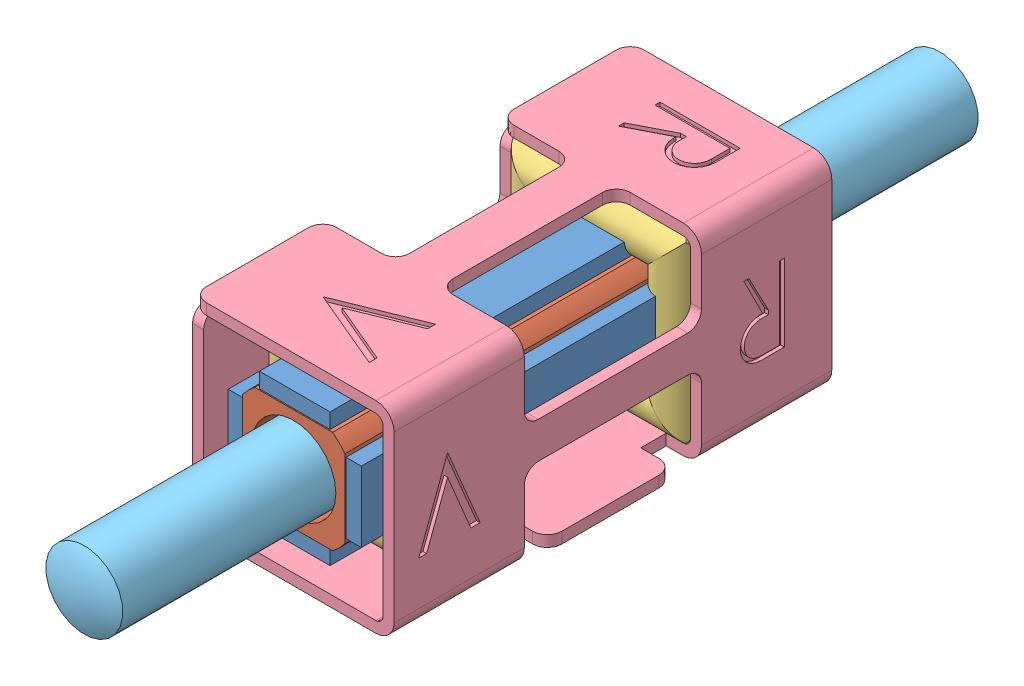
SolidWorks assembly SQL-RV-1.8-6-12_nocable.STEP, configuration Standard. Lengths in mm.
Overall size (2.77 2.77 12).
11 component instances, 5 part files, 0 mates.
Components (placement in the parent):
- 02356-3-0000-1: 02356-3-0000 [Default] at (-0.0043 -0.0117 0.0036) size (1.83 1.83 6)
  - 02094-0-0000-1: 02094-0-0000 [Default] at (53.8621 -453.2709 1) x (0 -1 0) z (-1 0 0) size (0.97 5.97 0.21)
  - 02094-0-0000-2: 02094-0-0000 [Default] at (55.2721 -453.2709 1) x (0 -1 0) z (1 0 0) size (0.97 5.97 0.21)
  - 01594-0-0000_drawing view-1: 01594-0-0000_drawing view [Default] at (54.5671 -453.2709 1) size (1.41 1.41 6)
  - 02094-0-0000-3: 02094-0-0000 [Default] at (54.5671 -453.9759 1) x (1 0 0) z (0 -1 0) size (0.97 5.97 0.21)
  - 02094-0-0000-4: 02094-0-0000 [Default] at (54.5671 -452.5659 1) x (1 0 0) z (0 1 0) size (0.97 5.97 0.21)
- 02914-3-0000_BENT-1: 02914-3-0000_BENT [Default] at (6.5476 -454.5988 11.0929) x (-1 0 0) z (0 -1 0) size (2.77 6.02 2.77)
  - 02559-0-0000_WRAPPED-1: 02559-0-0000_WRAPPED [Default] at (-46.7822 8.4293 -2.5496) x (0 1 0) z (0 0 1) size (1.23 2.47 2.48)
  - 02915-0-0000_Correct Wrap-1: 02915-0-0000_Correct Wrap [Default] at (-56.4542 13.0993 2.6363) x (1 0 0) z (0 0 -1) size (2.77 6.02 2.77)
  - 02559-0-0000_WRAPPED-2: 02559-0-0000_WRAPPED [Default] at (-46.7822 11.7593 -2.5496) x (0 1 0) z (0 0 1) size (1.23 2.47 2.48)
- 01593-0-1012_MODEL-1: 01593-0-1012_MODEL [Default] at (54.5629 -453.2826 7.0036) x (-0.809258 0.587453 0) z (0 0 1) size (1.11 1.08 12)
